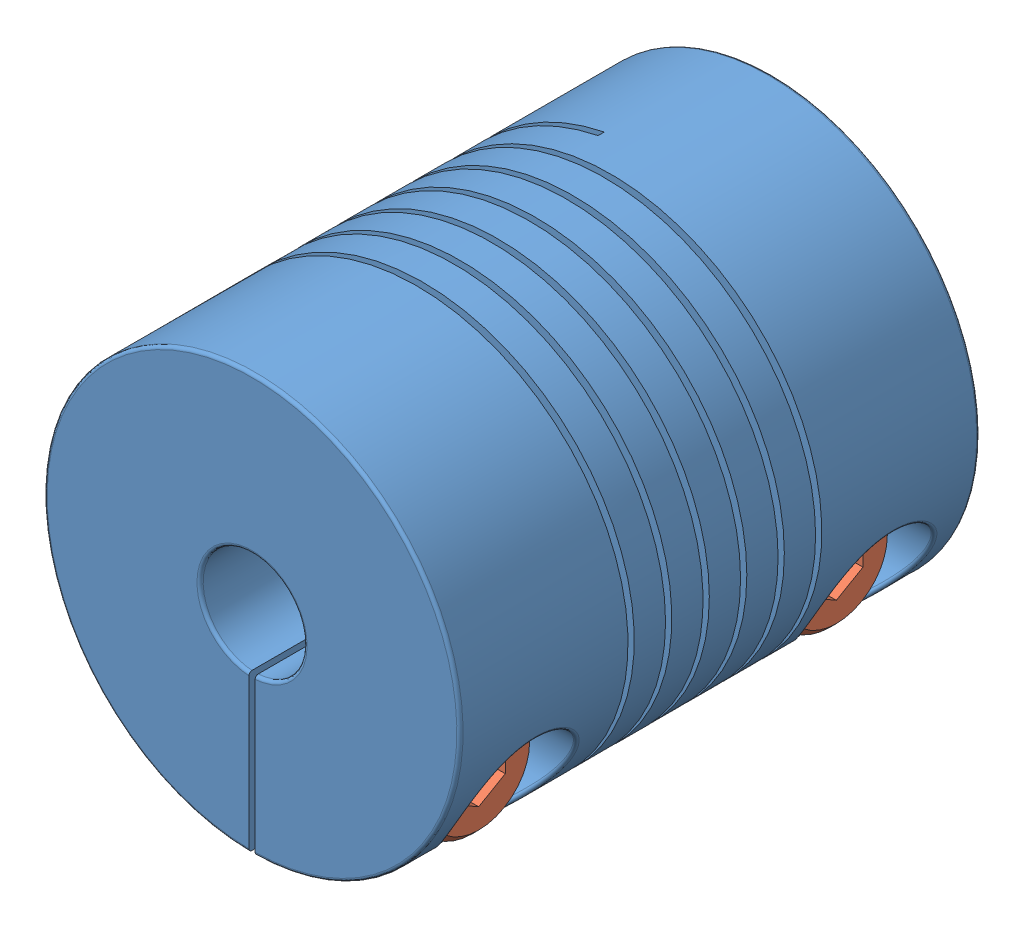
SolidWorks assembly 5mm x 6mm Flexible Coupling, configuration Default. Lengths in mm.
Overall size (20.7 20.83 25.02).
3 component instances, 2 part files, 4 mates.
Components (placement in the parent):
- 5mm x 6mm Flexible Coupling-1: 5mm x 6mm Flexible Coupling [Default] at (-56.2132 1.0794 41.4299) size (20.7 20.83 25.02)
- Socket Head Cap Screw_AM-4: Socket Head Cap Screw_AM [B18.3.1M - 3 x 0.5 x 12 Hex SHCS -- 12NHX] at (-49.2132 -3.9206 37.5299) x (-1 0 0) z (0 0 -1) size (15 5.5 5.5)
- Socket Head Cap Screw_AM-5: Socket Head Cap Screw_AM [B18.3.1M - 3 x 0.5 x 12 Hex SHCS -- 12NHX] at (-49.2132 -3.9206 20.3299) x (-1 0 0) z (0 0 -1) size (15 5.5 5.5)
Mates (geometry in assembly coordinates):
- Concentric3: concentric aligned: cylinder of 5mm x 6mm Flexible Coupling-1 through (-66.5647 -3.9206 37.5299) axis (1 0 0) radius 1.5; cylinder of Socket Head Cap Screw_AM-4 through (-17.4632 -3.9206 37.5299) axis (1 0 0) radius 1.5
- Coincident3: coincident anti-aligned: plane of 5mm x 6mm Flexible Coupling-1 through (-52.2132 -3.9206 37.5299) normal (1 0 0); plane of Socket Head Cap Screw_AM-4 through (-52.2132 -1.1706 37.5299) normal (-1 0 0)
- Coincident4: coincident anti-aligned: plane of 5mm x 6mm Flexible Coupling-1 through (-52.2132 -3.9206 20.3299) normal (1 0 0); plane of Socket Head Cap Screw_AM-5 through (-52.2132 -1.1706 20.3299) normal (-1 0 0)
- Concentric4: concentric aligned: cylinder of 5mm x 6mm Flexible Coupling-1 through (-66.5647 -3.9206 20.3299) axis (1 0 0) radius 1.5; cylinder of Socket Head Cap Screw_AM-5 through (-17.4632 -3.9206 20.3299) axis (1 0 0) radius 1.5
